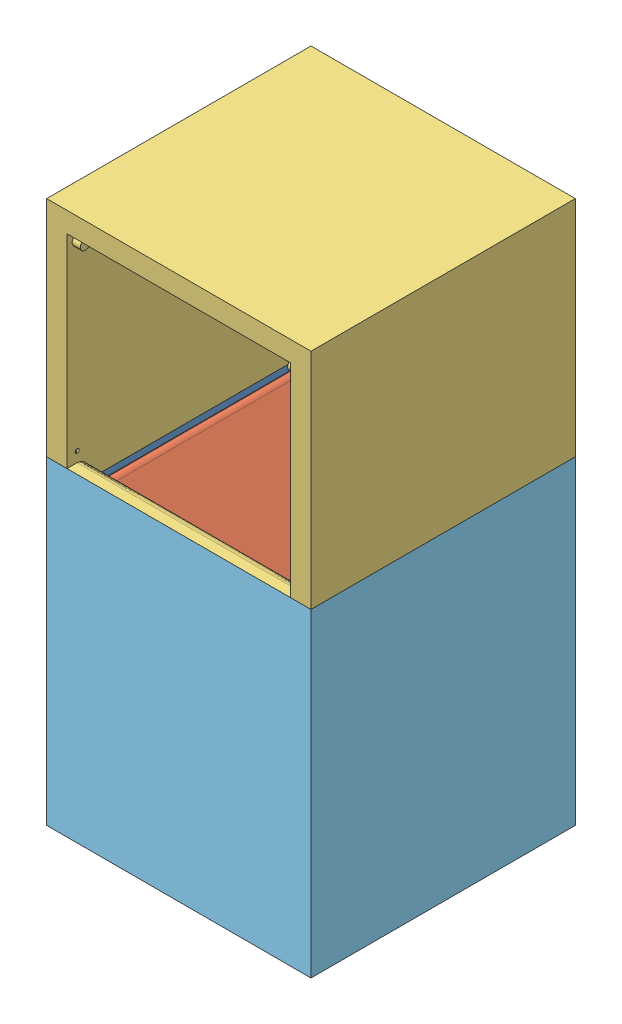
SolidWorks assembly Assem1, configuration Default. Lengths in mm.
Overall size (650 1335 650).
8 component instances, 5 part files, 0 mates.
Components (placement in the parent):
- Collar-1: (DuplicatedForAssembly)Collar [Default] at (159.3738 299.0546 504.1856) size (600 80 600)
- FlapV3-1: (DuplicatedForAssembly)FlapV3 [Default] at (159.0661 305.2301 504.2081) size (275 283.84 500)
- FlapV3-4: (DuplicatedForAssembly)FlapV3 [Default] at (159.0661 305.2301 504.2081) x (0 0 -1) z (1 0 0) size (275 283.84 500)
- FlapV3-5: (DuplicatedForAssembly)FlapV3 [Default] at (159.0661 305.2301 504.2081) x (0 0 1) z (-1 0 0) size (275 283.84 500)
- FlapV3-6: (DuplicatedForAssembly)FlapV3 [Default] at (159.0661 305.2301 504.2081) x (-1 0 0) z (0 0 -1) size (275 283.84 500)
- lid-1: (DuplicatedForAssembly)lid [Default] at (159.375 374.0559 504.2309) size (650 600 650)
- piHolder-1: (DuplicatedForAssembly)piHolder [Default] at (166.8458 873.9996 504.3628) size (85.02 15.22 64)
- Base-2: (DuplicatedForAssembly)Base [Default] at (159.375 349.0559 504.2309) size (650 785 650)
